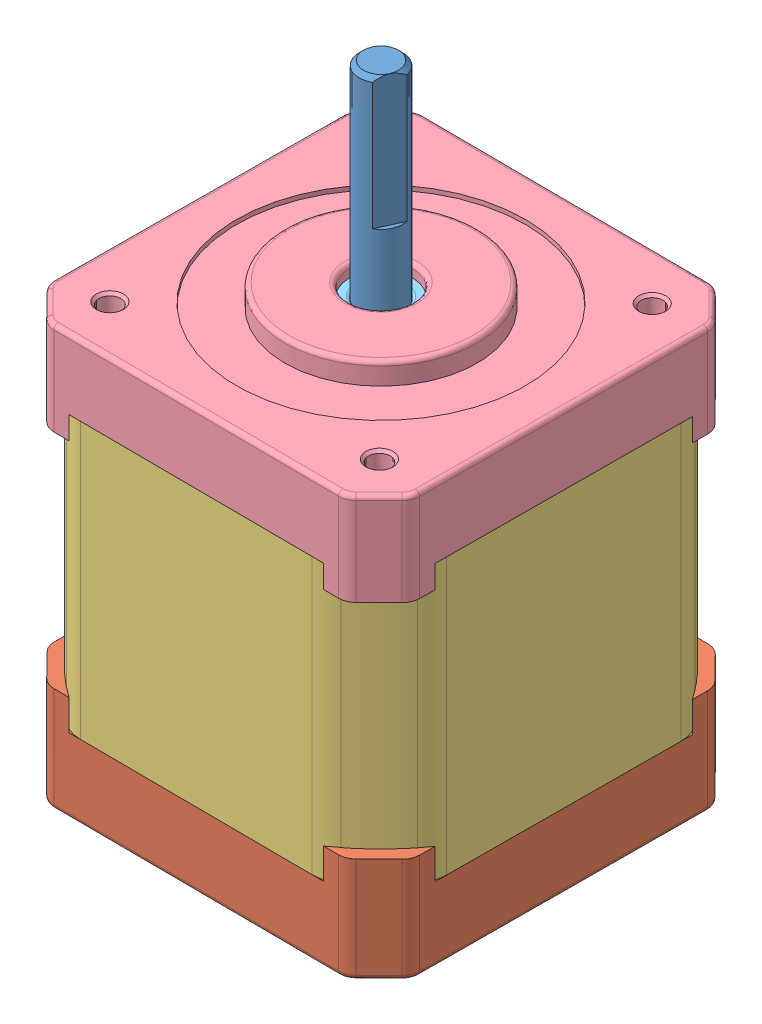
SolidWorks assembly 17HM19-2004S, configuration Default. Lengths in mm.
Overall size (42.24 72 42.24).
10 component instances, 6 part files, 0 mates.
Components (placement in the parent):
- nema17_shaft_17HM19-2004S-1: nema17_shaft_17HM19-2004S [Default] at (13.0746 21 -1.623) x (-0.412738 0 0.91085) z (-0.91085 0 -0.412738) size (5 72 5)
- nema17_bottom_17HM19-2004S-1: nema17_bottom_17HM19-2004S [Default] at (13.0746 21 -1.623) x (0.999984 0 0.005702) z (-0.005702 0 0.999984) size (42 12 42)
- nema17_middle_17HM19-2004S-1: nema17_middle_17HM19-2004S [Default] at (13.0746 29.5 -1.623) x (0.999984 0 0.005702) z (-0.005702 0 0.999984) size (42 31.5 42)
- nema17_top_17HM19-2004S-1: nema17_top_17HM19-2004S [Default] at (13.0746 61 -1.623) x (0.999984 0 0.005702) z (-0.005702 0 0.999984) size (42 12.6 42)
- radial ball bearing_68_din_DIN 625 - 625 - 8,SI,NC,8_68-1: radial ball bearing_68_din_DIN 625 - 625 - 8,SI,NC,8_68 [Default] at (13.0746 26 -1.623) x (0 -1 0) z (0 0 1) size (5.01 16 16)
- radial ball bearing_68_din_DIN 625 - 625 - 8,SI,NC,8_68-2: radial ball bearing_68_din_DIN 625 - 625 - 8,SI,NC,8_68 [Default] at (13.0746 67.1 -1.623) x (0 1 0) z (0 0 1) size (5.01 16 16)
- countersunk flat head cross recess screw_din_ISO 7046-1 - M3 x 30 - Z --- 30N-1: countersunk flat head cross recess screw_din_ISO 7046-1 - M3 x 30 - Z --- 30N [Default] at (28.4859 21.6 13.9651) x (0 1 0) z (0.546944 0 -0.837169) size (30 5.5 5.5)
- countersunk flat head cross recess screw_din_ISO 7046-1 - M3 x 30 - Z --- 30N-2: countersunk flat head cross recess screw_din_ISO 7046-1 - M3 x 30 - Z --- 30N [Default] at (28.6627 21.6 -17.0344) x (0 1 0) z (0.546944 0 -0.837169) size (30 5.5 5.5)
- countersunk flat head cross recess screw_din_ISO 7046-1 - M3 x 30 - Z --- 30N-3: countersunk flat head cross recess screw_din_ISO 7046-1 - M3 x 30 - Z --- 30N [Default] at (-2.5136 21.6 13.7883) x (0 1 0) z (0.546944 0 -0.837169) size (30 5.5 5.5)
- countersunk flat head cross recess screw_din_ISO 7046-1 - M3 x 30 - Z --- 30N-4: countersunk flat head cross recess screw_din_ISO 7046-1 - M3 x 30 - Z --- 30N [Default] at (-2.3368 21.6 -17.2112) x (0 1 0) z (0.546944 0 -0.837169) size (30 5.5 5.5)
